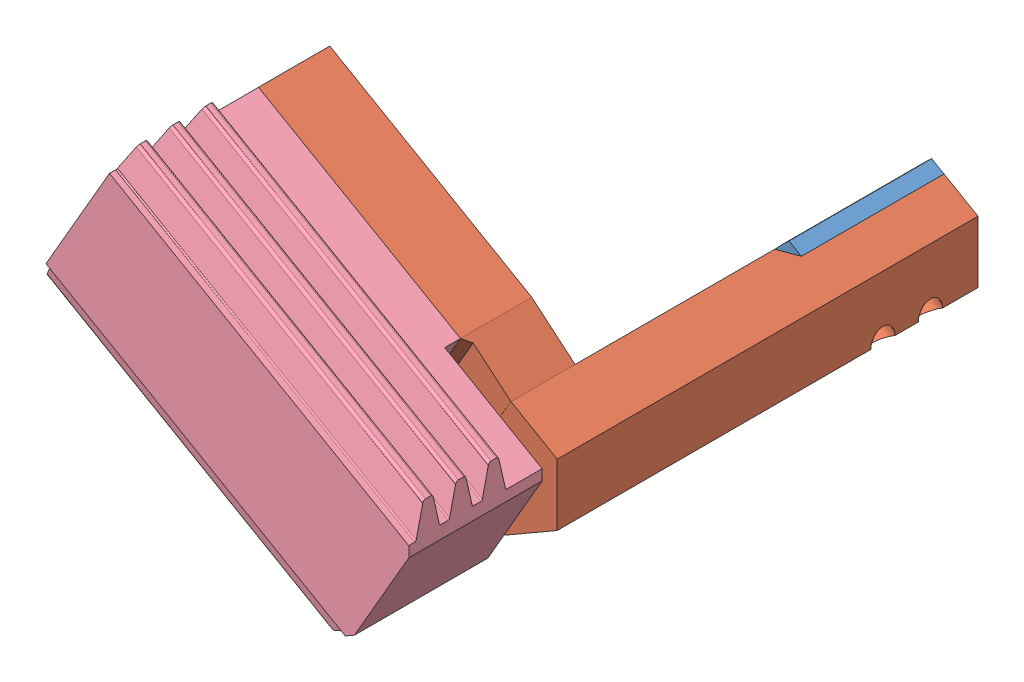
SolidWorks assembly chela_carrello, configuration Default. Lengths in mm.
Overall size (55.42 46.79 80.9).
8 component instances, 5 part files, 8 mates.
Components (placement in the parent):
- chela-1: chela [Default] at (-3.3677 6.4971 -10) size (49.79 38.22 63)
  - Gommino-1: Gommino [Default] at (3.3677 -6.4971 10) size (9.23 13.99 20)
  - Asta_chela-1: Asta_chela [Default] at (3.3677 -6.4971 10) size (49.79 38.22 63)
  - socket countersunk head screw_iso-2: socket countersunk head screw_iso [ISO 10642 - M3 x 8 - 8N] at (-8.32 0.2508 23.3333) x (0.866025 -0.5 0) z (0.497551 0.861784 0.098852) size (8 5.54 5.54)
  - socket countersunk head screw_iso-3: socket countersunk head screw_iso [ISO 10642 - M3 x 8 - 8N] at (-8.32 0.2508 16.6667) x (0.866025 -0.5 0) z (0.240379 0.416349 0.876853) size (8 5.54 5.54)
- SCHUNK_0303312_PZN_plus_100_1__00000_5-1: SCHUNK_0303312_PZN_plus_100_1__00000_5 [Default] at (-3.7239 2.15 80.9) x (0.5 0.866025 0) z (-0.866025 0.5 0) size (25.62 20.9 49.2)
- socket head cap screw_iso-1: socket head cap screw_iso [ISO 4762 M5 x 16 - 16N] at (-23.8157 13.75 48) x (0 0 1) z (0.866025 -0.5 0) size (21 8.5 8.5)
- socket head cap screw_iso-2: socket head cap screw_iso [ISO 4762 M5 x 16 - 16N] at (-41.1362 23.75 48) x (0 0 1) z (-0.977936 -0.208906 0) size (21 8.5 8.5)
Mates (geometry in assembly coordinates):
- Coincidente3: coordinate: point of chela-1/Gommino-1
- Coincidente4: coincident anti-aligned: plane of chela-1/Asta_chela-1 through (0 0 60) normal (0 0 1); plane of SCHUNK_0303312_PZN_plus_100_1__00000_5-1 through (-41.8824 34.4576 60) normal (0 0 -1)
- Concentrico1: concentric anti-aligned: cylinder of chela-1/Asta_chela-1 through (-23.8157 13.75 63) axis (0 0 -1) radius 5; cylinder of SCHUNK_0303312_PZN_plus_100_1__00000_5-1 through (-23.8157 13.75 76.0026) axis (0 0 1) radius 5
- Concentrico2: concentric anti-aligned: cylinder of chela-1/Asta_chela-1 through (-41.1362 23.75 63) axis (0 0 -1) radius 5; cylinder of SCHUNK_0303312_PZN_plus_100_1__00000_5-1 through (-41.1362 23.75 76.0026) axis (0 0 1) radius 5
- Coincidente5: coincident anti-aligned: plane of chela-1/Asta_chela-1 through (-23.8157 13.75 53) normal (0 0 -1); plane of socket head cap screw_iso-1 through (-25.9407 10.0694 53) normal (0 0 1)
- Concentrico3: concentric anti-aligned: cylinder of chela-1/Asta_chela-1 through (-23.8157 13.75 50) axis (0 0 1) radius 2.46; cylinder of socket head cap screw_iso-1 through (-23.8157 13.75 16.25) axis (0 0 -1) radius 2.5
- Coincidente6: coincident anti-aligned: plane of chela-1/Asta_chela-1 through (-41.1362 23.75 53) normal (0 0 -1); plane of socket head cap screw_iso-2 through (-42.0241 27.9062 53) normal (0 0 1)
- Concentrico4: concentric: cylinder of chela-1/Asta_chela-1 through (-41.1362 23.75 50) axis (0 0 1) radius 2.46; cylinder of socket head cap screw_iso-2 through (-41.1362 23.75 16.25) axis (0 0 -1) radius 2.5
